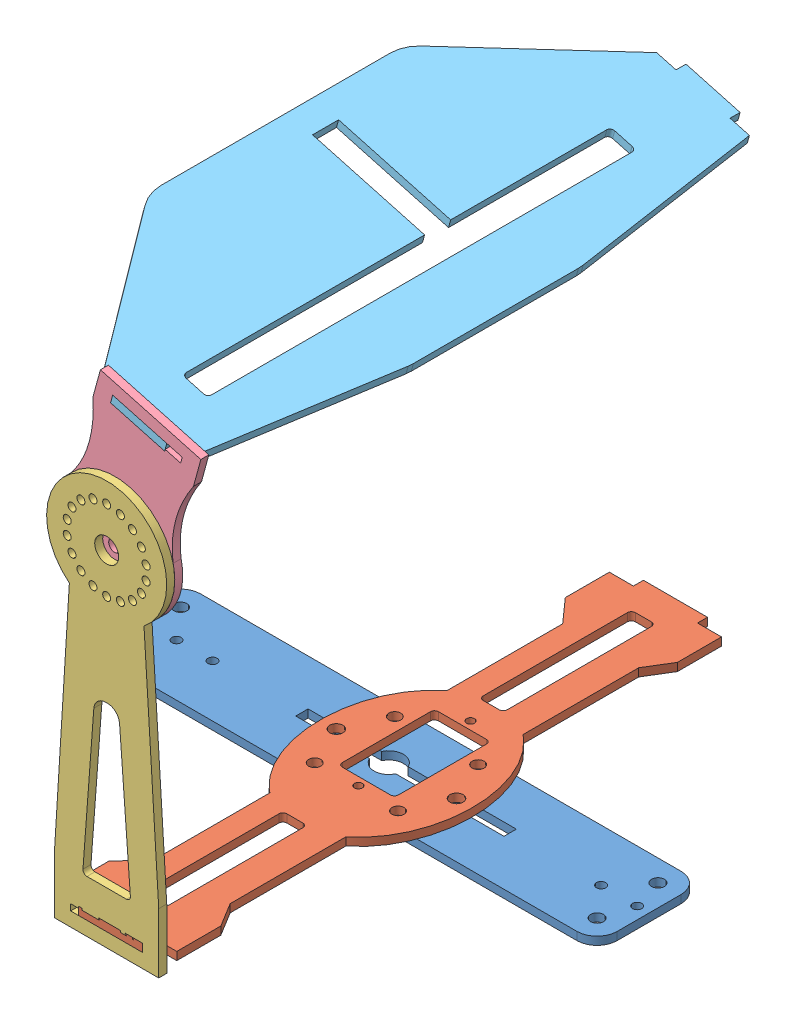
SolidWorks assembly trem_de_pouso, configuration Valor predeterminado. Lengths in mm.
Overall size (130 126.72 145.13).
5 component instances, 5 part files, 12 mates.
Components (placement in the parent):
- Peça1-1: Peça1 [Valor predeterminado] at (11.8384 18.378 130) size (130 2 26)
- Peça2-1: Peça2 [Valor predeterminado] at (15.0253 20.378 131.2803) x (0 0 -1) z (1 0 0) size (141 2 38)
- Peça5-1: Peça5 [Valor predeterminado] at (13.1892 102.878 201.7803) x (0 0 -1) z (1 0 0) size (2 101 30)
- Peça4-1: Peça4 [Valor predeterminado] at (13.1892 102.878 197.7803) x (0 0 1) z (-0.964541 0.263935 0) size (2 49 30)
- Peça3-1: Peça3 [Valor predeterminado] at (3.7801 135.5188 128.2131) x (0 0 1) z (-0.964541 0.263935 0) size (143.13 2 57)
Mates (geometry in assembly coordinates):
- Coincidente1: coincident anti-aligned: plane of Peça1-1 through (71.8384 20.378 122) normal (0 1 0); plane of Peça2-1 through (15.0253 20.378 131.2803) normal (0 -1 0)
- Paralelo1: parallel anti-aligned: line of Peça1-1 through (-53.1616 20.378 122) axis (0 0 1); line of Peça2-1 through (24.5253 20.378 182.2803) axis (0 0 -1)
- Bloquear1: lock: unknown of Peça1-1; unknown of Peça2-1
- Coincidente4: coincident: point of Peça2-1; plane of Peça5-1 through (22.1892 20.378 201.7803) normal (0 1 0)
- Coincidente5: coincident anti-aligned: line of Peça2-1 through (6.1892 20.378 201.7803) axis (1 0 0); line of Peça5-1 through (22.1892 20.378 201.7803) axis (-1 0 0)
- Coincidente6: coincident anti-aligned: plane of Peça2-1 through (22.1892 22.378 199.2803) normal (1 0 0); plane of Peça5-1 through (22.1892 21.9394 201.7803) normal (-1 0 0)
- Concêntrico1: concentric anti-aligned: circle of Peça5-1; cylinder of Peça4-1 through (13.1892 102.878 197.7803) axis (0 0 1) radius 1.5
- Coincidente7: coincident anti-aligned: plane of Peça5-1 through (13.1892 102.878 199.7803) normal (0 0 -1); plane of Peça4-1 through (6.7644 121.9117 199.7803) normal (0 0 1)
- Paralelo2: parallel anti-aligned: line of Peça4-1 through (12.287 133.6804 197.7803) axis (0.964541 -0.263935 0); line of Peça3-1 through (26.1938 131.459 199.7803) axis (-0.964541 0.263935 0)
- Coincidente9: coincident anti-aligned: plane of Peça4-1 through (12.6903 135.1541 197.7803) normal (-0.263935 -0.964541 0); plane of Peça3-1 through (27.1584 131.1951 107.6156) normal (0.263935 0.964541 0)
- Coincidente10: coincident anti-aligned: plane of Peça4-1 through (12.6903 135.1541 197.7803) normal (0.964541 -0.263935 0); plane of Peça3-1 through (12.6903 135.1541 197.2803) normal (-0.964541 0.263935 0)
- Coincidente11: coincident aligned: plane of Peça4-1 through (6.7644 121.9117 199.7803) normal (0 0 1); plane of Peça3-1 through (12.6903 135.1541 199.7803) normal (0 0 1)
